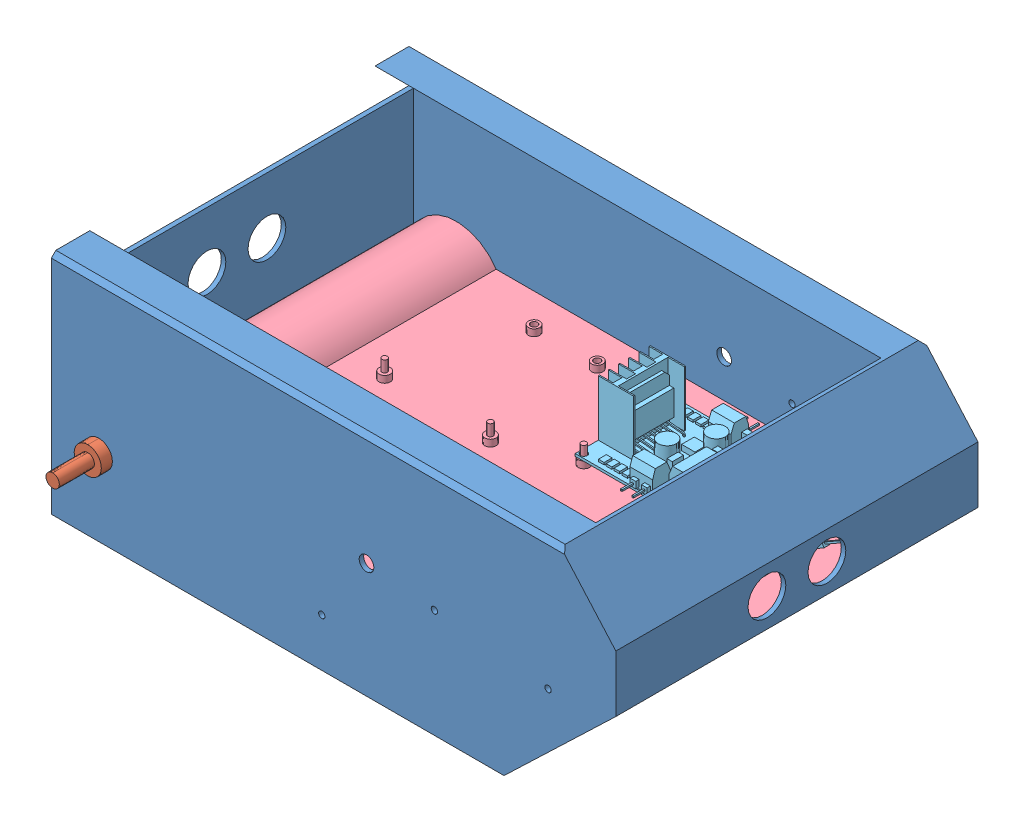
SolidWorks assembly Box for Tracks, configuration Standard. Lengths in mm.
Overall size (249.41 100 200.85).
7 component instances, 6 part files, 12 mates.
Components (placement in the parent):
- Box-1: Box [Standard] at (-47.2891 -14.6729 181.4058) size (249.41 100 160)
- motor.step-1: motor.step [Standard] at (-130.1233 -32.1815 288.0058) x (-0.999923 0.012371 0) z (0.012371 0.999923 0) size (37.1 151.83 37.1)
- motor.step-2: motor.step [Standard] at (-129.9085 -32.1821 234.7599) x (0.999976 0.006987 0) z (-0.006987 0.999976 0) size (37.1 151.83 37.1)
- Battery-1: Battery [Standard] at (-17.7169 -18.8624 235.416) x (1 0.0007 0) z (0 0 1) size (142 30 52)
- Layer-2_Mounting-1: Layer-2_Mounting [Standard] at (50.0233 -22.58 339.1058) x (-1 -0.0007 0) z (0 0 -1) size (216.69 23.92 155.7)
- motorcontroler.step-1: motorcontroler.step [Default] at (1.3758 -17.6141 218.9058) x (0 0 1) z (-1 -0.0007 0) size (55.7 26.71 104.61)
- hex thin nut chamfered gradeab_din-3: hex thin nut chamfered gradeab_din [Hexagon Thin Nut ISO 4035 - M2.5 - N] at (-18.4242 -26.1924 199.1058) x (0.86683 0 0.498604) z (0 -1 0) size (5 5.77 1.6)
Mates (geometry in assembly coordinates):
- Concentric1: concentric: circle of Box-1; cylinder of motor.step-1 through (-129.986 -21.0824 361.8058) axis (0 0 -1) radius 2.95
- Concentric2: concentric anti-aligned: circle of Box-1; circle of motor.step-2
- Coincident1: coincident: plane of Box-1 through (-150.986 -52.6924 341.4058) normal (0 1 0); line of Battery-1 through (-110.476 -52.6924 287.416) axis (0 0 -1)
- Coincident14: coincident anti-aligned: plane of Box-1 through (-47.2891 -14.6729 339.4058) normal (0 0 -1); plane of motor.step-1 through (-130.1233 -32.1815 339.4058) normal (0 0 1)
- Concentric3: concentric anti-aligned: cylinder of motor.step-1 through (-130.1233 -32.1815 317.4058) axis (0 0 -1) radius 17.325; cylinder of Layer-2_Mounting-1 through (-130.1233 -32.1815 183.4058) axis (0 0 1) radius 19.05
- Coincident15: coincident anti-aligned: plane of Box-1 through (-47.2891 -14.6729 183.4058) normal (0 0 1); plane of Layer-2_Mounting-1 through (-130.1233 -32.1815 183.4058) normal (0 0 -1)
- Coincident16: coincident anti-aligned: plane of Battery-1 through (-110.497 -22.6924 287.416) normal (-0.0007 1 0); plane of Layer-2_Mounting-1 through (-108.1898 -22.6908 183.4058) normal (0.0007 -1 0)
- Concentric4: concentric aligned: circle of Layer-2_Mounting-1; circle of motorcontroler.step-1
- Concentric5: concentric anti-aligned: cylinder of Layer-2_Mounting-1 through (21.1723 -12.6002 238.7058) axis (0.0007 -1 0) radius 1.2; circle of motorcontroler.step-1
- Coincident17: coincident: plane of Layer-2_Mounting-1 through (-18.4242 -17.6279 238.7058) normal (-0.0007 1 0); line of motorcontroler.step-1 through (-20.3242 -17.6293 240.6058) axis (1 0.0007 0)
- Concentric6: concentric: cylinder of Box-1 through (-18.4242 -24.6924 199.1058) axis (0 -1 0) radius 2; circle of hex thin nut chamfered gradeab_din-3
- Coincident19: coincident anti-aligned: plane of Box-1 through (-47.2891 -26.1924 181.4058) normal (0 1 0); plane of hex thin nut chamfered gradeab_din-3 through (-19.8636 -26.1924 201.6081) normal (0 -1 0)
